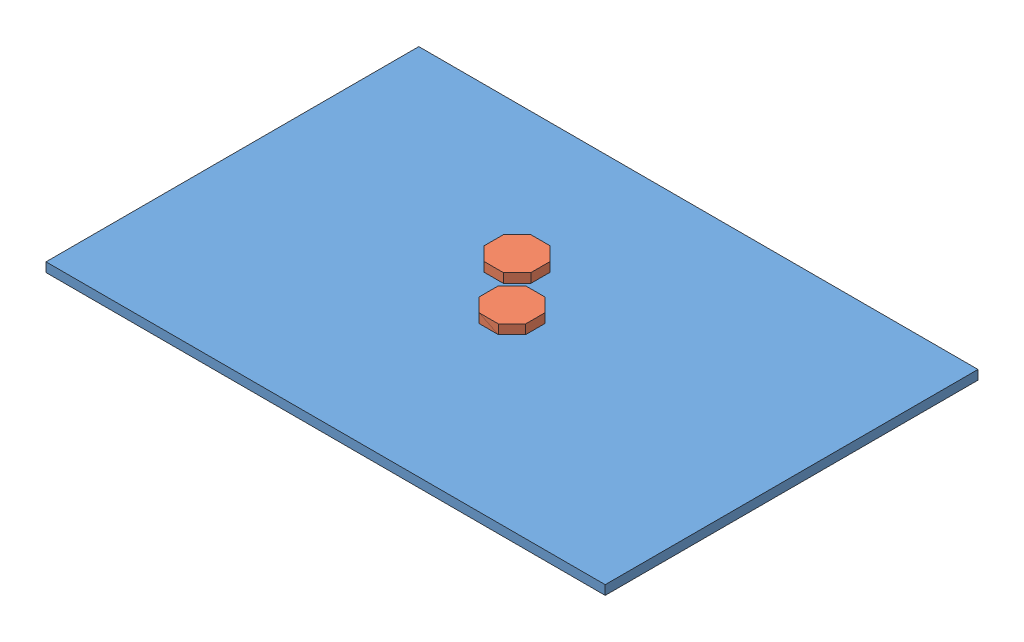
SolidWorks assembly two_node_4500, configuration Default. Lengths in mm.
Overall size (600 25 400).
3 component instances, 2 part files, 6 mates.
Components (placement in the parent):
- ground-1: ground [Default] at origin size (600 10 400)
- node_4500-1: node_4500 [Default] at origin size (50 10 50)
- node_4500-2: node_4500 [Default] at (-39.8464 5 -45.3392) size (50 10 50)
Mates (geometry in assembly coordinates):
- Coincident1: coincident aligned: plane of ground-1 through (0 0 0) normal (0 0 1)
- Coincident2: coincident aligned: plane of ground-1 through (0 0 0) normal (0 1 0)
- Coincident3: coincident aligned: plane of ground-1 through (0 0 0) normal (1 0 0)
- Coincident4: coincident aligned: plane of node_4500-1 through (-28.8782 0 0) normal (0 0 1)
- Coincident5: coincident aligned: plane of node_4500-1 through (-28.8782 0 0) normal (0 1 0)
- Coincident6: coincident aligned: plane of node_4500-1 through (0 0 0) normal (1 0 0)
